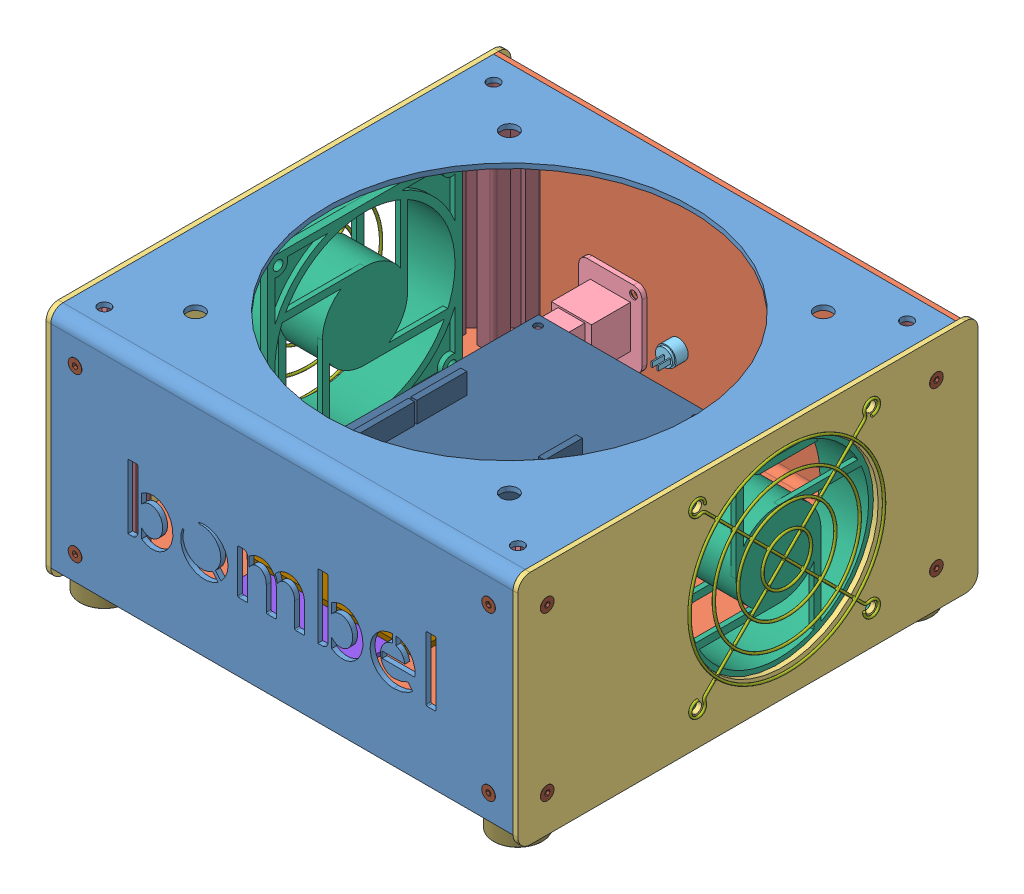
SolidWorks assembly 1 Case, configuration Domyślna. Lengths in mm.
Overall size (197.9 100.39 189.25).
41 component instances, 17 part files, 82 mates.
Components (placement in the parent):
- 1.1.2 top_panel_front-1: 1.1.2 top_panel_front [Domyślna] at origin size (190 92 182)
- 1.1.3 bottom_back-1: 1.1.3 bottom_back [Domyślna] at (0 -90 0) size (190 92 182)
- 1.1.4 side-1: 1.1.4 side [Domyślna] at (97 -94 27.8528) size (2 97 189.15)
- 1.1.4 side-2: 1.1.4 side [Domyślna] at (-95 -94 27.8528) size (2 97 189.15)
- 1.2.1 stop button-1: 1.2.1 stop button [Domyślna] at (-67.6862 -22.4205 120.7297) x (1 0 0) z (0 -0.573576 0.819152) size (37 74 39) (hidden)
- 1.2.4 usb-1: 1.2.4 usb [Domyślna] at (-45 -67 -90) x (-1 0 0) z (0 0 -1) size (26 31 41.5)
- 1.2.3 power socket-1: 1.2.3 power socket [Domyślna] at (-19 -67 -96) x (1 0 0) z (0 0 -1) size (10 10 17)
- 1.2.2 fan 80-1: 1.2.2 fan 80 [Domyślna] at (85 -46.7 -17.1472) x (0 0 1) z (-1 0 0) size (80 80 20.01)
- 1.2.2 fan 80-2: 1.2.2 fan 80 [Domyślna] at (-85 -46.7 -17.1472) x (0 0 -1) z (1 0 0) size (80 80 20.01)
- 1.2.9 fan barrier-1: 1.2.9 fan barrier [Domyślna] at (97.5 -46.7 -17.1472) x (0 0 -1) z (1 0 0) size (81 81 1.9)
- 1.2.6 screen-1: 1.2.6 screen [Domyślna] at (-6.25 -20.8447 110.4623) x (1 0 0) z (0 -0.573576 0.819152) size (77.5 14.2 42.8) (hidden)
- 1.2.7 joystick-1: 1.2.7 joystick [Domyślna] at (63.75 -22.9474 119.9159) x (1 0 0) z (0 -0.573576 0.819152) size (52.5 133.13 52.5) (hidden)
- 1.2.5 elektronika-1: 1.2.5 elektronika [Domyślna] at (-11.5 -80 35) x (0 0 -1) z (1 0 0) size (129 45 75.5)
  - 1.2.5.1 plytka podstawa-1: 1.2.5.1 plytka podstawa [Domyślna] at origin size (88 10 55)
  - 1.2.5.2 nucleo-f411re-1: 1.2.5.2 nucleo-f411re [Domyślna] at (1.6807 11.5 7.1981) x (-1 0 0) z (0 0 -1) size (82.5 19 70)
  - 1.2.5.3 x-nucleo-ihm02a1-1: 1.2.5.3 x-nucleo-ihm02a1 [Domyślna] at (39 23.5 11.5) size (92 18.5 73)
  - 1.2.5.3 x-nucleo-ihm02a1-2: 1.2.5.3 x-nucleo-ihm02a1 [Domyślna] at (39 35 11.5) size (92 18.5 73)
- 1.2.8 buttons-1: 1.2.8 buttons [Domyślna] at (-8.25 -47.2433 131.775) x (1 0 0) z (0 -0.573576 0.819152) size (76 7.6 17.4) (hidden)
- 1.2.9 fan barrier-2: 1.2.9 fan barrier [Domyślna] at (-97.5 -46.7 -17.1472) x (0 0 1) z (-1 0 0) size (81 81 1.9)
- socket csink head cap screw 10642_din-2: socket csink head cap screw 10642_din [EN ISO 10642 - M3 x 8 - 8N] at (85 -82 92.1) x (0 0 -1) z (-0.284698 0.958617 0) size (8 5.54 5.54)
- socket csink head cap screw 10642_din-3: socket csink head cap screw 10642_din [EN ISO 10642 - M3 x 8 - 8N] at (85 -15 92.1) x (0 0 -1) z (-0.433088 0.901352 0) size (8 5.54 5.54)
- socket csink head cap screw 10642_din-5: socket csink head cap screw 10642_din [EN ISO 10642 - M3 x 8 - 8N] at (97.1 -15 80) x (-1 0 0) z (0 0.725657 0.688057) size (8 5.54 5.54)
- socket csink head cap screw 10642_din-7: socket csink head cap screw 10642_din [EN ISO 10642 - M3 x 8 - 8N] at (97.1 -82 80) x (-1 0 0) z (0 0.659411 0.751782) size (8 5.54 5.54)
- socket csink head cap screw 10642_din-9: socket csink head cap screw 10642_din [EN ISO 10642 - M3 x 8 - 8N] at (-85 -15 92.1) x (0 0 -1) z (-0.661943 0.749554 0) size (8 5.54 5.54)
- socket csink head cap screw 10642_din-11: socket csink head cap screw 10642_din [EN ISO 10642 - M3 x 8 - 8N] at (-85 -82 92.1) x (0 0 -1) z (-0.669203 0.743079 0) size (8 5.54 5.54)
- socket csink head cap screw 10642_din-13: socket csink head cap screw 10642_din [EN ISO 10642 - M3 x 8 - 8N] at (-97.1 -15 80) x (1 0 0) z (0 0.345644 0.938366) size (8 5.54 5.54)
- socket csink head cap screw 10642_din-15: socket csink head cap screw 10642_din [EN ISO 10642 - M3 x 8 - 8N] at (-97.1 -82 80) x (1 0 0) z (0 0.223396 0.974728) size (8 5.54 5.54)
- socket csink head cap screw 10642_din-17: socket csink head cap screw 10642_din [EN ISO 10642 - M3 x 8 - 8N] at (-97.1 -15 -80) x (1 0 0) z (0 0.068735 0.997635) size (8 5.54 5.54)
- socket csink head cap screw 10642_din-19: socket csink head cap screw 10642_din [EN ISO 10642 - M3 x 8 - 8N] at (-97.1 -82 -80) x (1 0 0) z (0 -0.102923 0.994689) size (8 5.54 5.54)
- socket csink head cap screw 10642_din-21: socket csink head cap screw 10642_din [EN ISO 10642 - M3 x 8 - 8N] at (-85 -15 -92.1) x (0 0 1) z (0.113911 0.993491 0) size (8 5.54 5.54)
- socket csink head cap screw 10642_din-23: socket csink head cap screw 10642_din [EN ISO 10642 - M3 x 8 - 8N] at (85 -15 -92.1) x (0 0 1) z (-0.060338 0.998178 0) size (8 5.54 5.54)
- socket csink head cap screw 10642_din-25: socket csink head cap screw 10642_din [EN ISO 10642 - M3 x 8 - 8N] at (97.1 -15 -80) x (-1 0 0) z (0 0.986031 -0.166559) size (8 5.54 5.54)
- socket csink head cap screw 10642_din-27: socket csink head cap screw 10642_din [EN ISO 10642 - M3 x 8 - 8N] at (97.1 -82 -80) x (-1 0 0) z (0 0.96763 -0.252373) size (8 5.54 5.54)
- 1.1.8 foot-1: 1.1.8 foot [Domyślna] at (85 -100.3918 80) size (20 8.39 20)
- 1.1.8 foot-2: 1.1.8 foot [Domyślna] at (-85 -100.3918 80) x (0.982082 0 -0.188455) z (0.188455 0 0.982082) size (20 8.39 20)
- 1.1.8 foot-3: 1.1.8 foot [Domyślna] at (-85 -100.3918 -80) x (0.918365 0 -0.395734) z (0.395734 0 0.918365) size (20 8.39 20)
- 1.1.8 foot-4: 1.1.8 foot [Domyślna] at (85 -100.3918 -80) x (0.8 0 -0.6) z (0.6 0 0.8) size (20 8.39 20)
- 1.1.1 Profil 2020-3: 1.1.1 Profil 2020 [Domyślna] at (85 -87 -80) size (20 85 20)
- 1.1.1 Profil 2020-4: 1.1.1 Profil 2020 [Domyślna] at (-85 -87 -80) size (20 85 20)
- 1.1.1 Profil 2020-6: 1.1.1 Profil 2020 [Domyślna] at (-85 -5 80) x (1 0 0) z (0 0 -1) size (20 85 20)
- 1.1.1 Profil 2020-8: 1.1.1 Profil 2020 [Domyślna] at (85 -5 80) x (1 0 0) z (0 0 -1) size (20 85 20)
Mates (geometry in assembly coordinates):
- Wspólnie1: coordinate: point of 1.1.2 top_panel_front-1; point of assembly
- Wspólnie18: coincident anti-aligned: plane of 1.1.3 bottom_back-1 through (95 -90 -90) normal (0 0 1); plane of 1.2.4 usb-1 through (-45 -67 -90) normal (0 0 -1)
- Koncentryczne7: concentric anti-aligned: cylinder of 1.1.3 bottom_back-1 through (-45 -67 -82) axis (0 0 -1) radius 12; cylinder of 1.2.4 usb-1 through (-45 -67 -93) axis (0 0 1) radius 12
- Koncentryczne9: concentric aligned: cylinder of 1.1.3 bottom_back-1 through (-35.5 -55 -82) axis (0 0 -1) radius 1.75; cylinder of 1.2.4 usb-1 through (-35.5 -55 -90) axis (0 0 -1) radius 1.6
- Wspólnie19: coincident anti-aligned: plane of 1.1.3 bottom_back-1 through (95 -90 -92) normal (0 0 -1); plane of 1.2.3 power socket-1 through (-19 -71 -92) normal (0 0 1)
- Koncentryczne10: concentric aligned: cylinder of 1.1.3 bottom_back-1 through (-19 -67 -82) axis (0 0 -1) radius 4; cylinder of 1.2.3 power socket-1 through (-19 -67 -119.6978) axis (0 0 -1) radius 4
- Wspólnie20: coincident anti-aligned: plane of 1.1.4 side-1 through (95 -94 27.8528) normal (-1 0 0); plane of 1.2.2 fan 80-1 through (95 -46.7 -17.1472) normal (1 0 0)
- Koncentryczne11: concentric aligned: cylinder of 1.1.4 side-1 through (87 -10.95 -52.8972) axis (1 0 0) radius 2.1; cylinder of 1.2.2 fan 80-1 through (95 -10.95 -52.8972) axis (1 0 0) radius 2
- Koncentryczne12: concentric aligned: cylinder of 1.1.4 side-1 through (87 -10.95 18.6028) axis (1 0 0) radius 2.1; cylinder of 1.2.2 fan 80-1 through (95 -10.95 18.6028) axis (1 0 0) radius 2
- Wspólnie21: coincident anti-aligned: plane of 1.1.4 side-2 through (-95 -94 27.8528) normal (1 0 0); plane of 1.2.2 fan 80-2 through (-95 -46.7 -17.1472) normal (-1 0 0)
- Koncentryczne13: concentric anti-aligned: cylinder of 1.1.4 side-2 through (-105 -10.95 18.6028) axis (1 0 0) radius 2.1; cylinder of 1.2.2 fan 80-2 through (-95 -10.95 18.6028) axis (-1 0 0) radius 2
- Koncentryczne15: concentric anti-aligned: cylinder of 1.1.4 side-2 through (-105 -10.95 -52.8972) axis (1 0 0) radius 2.1; cylinder of 1.2.2 fan 80-2 through (-95 -10.95 -52.8972) axis (-1 0 0) radius 2
- Równolegle4: parallel aligned: plane of 1.2.5 elektronika-1/1.2.5.1 plytka podstawa-1 through (-11.5 -80 35) normal (0 1 0); plane of assembly through (0 0 0) normal (0 1 0)
- Wspólnie30: coincident aligned: plane of 1.1.3 bottom_back-1 through (95 0 -90) normal (0 1 0); plane of 1.1.2 top_panel_front-1 through (95 0 -90) normal (0 1 0)
- Wspólnie31: coincident anti-aligned: plane of 1.1.3 bottom_back-1 through (-95 -87 -87) normal (-1 0 0); plane of 1.1.4 side-2 through (-95 -94 27.8528) normal (1 0 0)
- Wspólnie34: coincident anti-aligned: plane of 1.1.2 top_panel_front-1 through (-95 -5 92) normal (-1 0 0); plane of 1.1.4 side-2 through (-95 -94 27.8528) normal (1 0 0)
- Wspólnie35: coincident anti-aligned: plane of 1.1.2 top_panel_front-1 through (95 -5 87) normal (1 0 0); plane of 1.1.4 side-1 through (95 -94 27.8528) normal (-1 0 0)
- Odległość3: distance = 10 mm anti-aligned: plane of 1.2.5 elektronika-1/1.2.5.1 plytka podstawa-1 through (-11.5 -80 35) normal (0 -1 0); plane of 1.1.3 bottom_back-1 through (95 -90 90) normal (0 1 0)
- Odległość4: distance = 40 mm anti-aligned: plane of 1.1.3 bottom_back-1 through (95 -90 -90) normal (0 0 1); plane of 1.2.5 elektronika-1/1.2.5.3 x-nucleo-ihm02a1-2 through (-36.5 -43.5 -50) normal (0 0 -1)
- Szerokość2: width anti-aligned: plane of 1.2.5 elektronika-1/1.2.5.3 x-nucleo-ihm02a1-2 through (36.5 -43.5 -50) normal (1 0 0); plane of 1.2.5 elektronika-1/1.2.5.3 x-nucleo-ihm02a1-2 through (-36.5 -43.5 42) normal (-1 0 0); plane of 1.1.4 side-2 through (-97 -94 27.8528) normal (-1 0 0); plane of 1.1.4 side-1 through (97 -94 27.8528) normal (1 0 0)
- Odległość5: distance = 0.5 mm aligned: plane of 1.2.9 fan barrier-1 through (97.5 -46.7 -17.1472) normal (1 0 0); plane of 1.1.4 side-1 through (97 -94 27.8528) normal (1 0 0)
- Równolegle5: parallel aligned: plane of 1.2.9 fan barrier-1 through (97.5 -46.7 -17.1472) normal (0 1 0); plane of assembly through (0 0 0) normal (0 1 0)
- Koncentryczne21: concentric aligned: cylinder of 1.1.4 side-1 through (87 -46.7 -17.1472) axis (1 0 0) radius 39; line of 1.2.9 fan barrier-1 through (96.95 -46.7 -17.1472) axis (1 0 0)
- Równolegle7: parallel aligned: plane of 1.2.1 stop button-1 through (-67.6862 -22.4205 120.7297) normal (1 0 0); plane of assembly through (0 0 0) normal (1 0 0)
- Równolegle8: parallel aligned: plane of 1.2.7 joystick-1 through (63.75 -22.9474 119.9159) normal (1 0 0); plane of assembly through (0 0 0) normal (1 0 0)
- Równolegle9: parallel aligned: plane of 1.2.3 power socket-1 through (-19 -67 -96) normal (1 0 0); plane of assembly through (0 0 0) normal (1 0 0)
- Odległość6: distance = 0.5 mm aligned: plane of 1.2.9 fan barrier-2 through (-97.5 -46.7 -17.1472) normal (-1 0 0); plane of 1.1.4 side-2 through (-97 -94 27.8528) normal (-1 0 0)
- Równolegle10: parallel aligned: plane of 1.2.9 fan barrier-2 through (-97.5 -46.7 -17.1472) normal (0 1 0); plane of assembly through (0 0 0) normal (0 1 0)
- Koncentryczne22: concentric anti-aligned: cylinder of 1.1.4 side-2 through (-105 -46.7 -17.1472) axis (1 0 0) radius 39; line of 1.2.9 fan barrier-2 through (-96.95 -46.7 -17.1472) axis (-1 0 0)
- Koncentryczne24: concentric aligned: cylinder of 1.1.2 top_panel_front-1 through (85 -82 82) axis (0 0 1) radius 1.5; cylinder of socket csink head cap screw 10642_din-2 through (85 -82 92.1) axis (0 0 1) radius 1.5
- Odległość7: distance = 0.1 mm aligned: plane of 1.1.2 top_panel_front-1 through (95 -2 92) normal (0 0 1); plane of socket csink head cap screw 10642_din-2 through (85 -82 92.1) normal (0 0 1)
- Koncentryczne25: concentric aligned: cylinder of 1.1.2 top_panel_front-1 through (85 -15 82) axis (0 0 1) radius 1.5; cylinder of socket csink head cap screw 10642_din-3 through (85 -15 92.1) axis (0 0 1) radius 1.5
- Odległość8: distance = 0.1 mm aligned: plane of 1.1.2 top_panel_front-1 through (95 -2 92) normal (0 0 1); plane of socket csink head cap screw 10642_din-3 through (85 -15 92.1) normal (0 0 1)
- Koncentryczne26: concentric aligned: cylinder of 1.1.4 side-1 through (87 -15 80) axis (1 0 0) radius 1.5; cylinder of socket csink head cap screw 10642_din-5 through (97.1 -15 80) axis (1 0 0) radius 1.5
- Odległość9: distance = 0.1 mm aligned: plane of 1.1.4 side-1 through (97 -94 27.8528) normal (1 0 0); plane of socket csink head cap screw 10642_din-5 through (97.1 -15 80) normal (1 0 0)
- Koncentryczne27: concentric aligned: cylinder of 1.1.4 side-1 through (87 -82 80) axis (1 0 0) radius 1.5; cylinder of socket csink head cap screw 10642_din-7 through (97.1 -82 80) axis (1 0 0) radius 1.5
- Odległość10: distance = 0.1 mm aligned: plane of 1.1.4 side-1 through (97 -94 27.8528) normal (1 0 0); plane of socket csink head cap screw 10642_din-7 through (97.1 -82 80) normal (1 0 0)
- Koncentryczne28: concentric aligned: cylinder of 1.1.2 top_panel_front-1 through (-85 -15 82) axis (0 0 1) radius 1.5; cylinder of socket csink head cap screw 10642_din-9 through (-85 -15 92.1) axis (0 0 1) radius 1.5
- Odległość11: distance = 0.1 mm aligned: plane of 1.1.2 top_panel_front-1 through (95 -2 92) normal (0 0 1); plane of socket csink head cap screw 10642_din-9 through (-85 -15 92.1) normal (0 0 1)
- Koncentryczne29: concentric aligned: cylinder of 1.1.2 top_panel_front-1 through (-85 -82 82) axis (0 0 1) radius 1.5; cylinder of socket csink head cap screw 10642_din-11 through (-85 -82 92.1) axis (0 0 1) radius 1.5
- Odległość12: distance = 0.1 mm aligned: plane of 1.1.2 top_panel_front-1 through (95 -2 92) normal (0 0 1); plane of socket csink head cap screw 10642_din-11 through (-85 -82 92.1) normal (0 0 1)
- Koncentryczne30: concentric anti-aligned: cylinder of 1.1.4 side-2 through (-105 -15 80) axis (1 0 0) radius 1.5; cylinder of socket csink head cap screw 10642_din-13 through (-97.1 -15 80) axis (-1 0 0) radius 1.5
- Odległość13: distance = 0.1 mm aligned: plane of 1.1.4 side-2 through (-97 -94 27.8528) normal (-1 0 0); plane of socket csink head cap screw 10642_din-13 through (-97.1 -15 80) normal (-1 0 0)
- Koncentryczne31: concentric anti-aligned: cylinder of 1.1.4 side-2 through (-105 -82 80) axis (1 0 0) radius 1.5; cylinder of socket csink head cap screw 10642_din-15 through (-97.1 -82 80) axis (-1 0 0) radius 1.5
- Odległość14: distance = 0.1 mm aligned: plane of 1.1.4 side-2 through (-97 -94 27.8528) normal (-1 0 0); plane of socket csink head cap screw 10642_din-15 through (-97.1 -82 80) normal (-1 0 0)
- Koncentryczne32: concentric anti-aligned: cylinder of 1.1.4 side-2 through (-105 -15 -80) axis (1 0 0) radius 1.5; cylinder of socket csink head cap screw 10642_din-17 through (-97.1 -15 -80) axis (-1 0 0) radius 1.5
- Odległość15: distance = 0.1 mm aligned: plane of 1.1.4 side-2 through (-97 -94 27.8528) normal (-1 0 0); plane of socket csink head cap screw 10642_din-17 through (-97.1 -15 -80) normal (-1 0 0)
- Koncentryczne33: concentric anti-aligned: cylinder of 1.1.4 side-2 through (-105 -82 -80) axis (1 0 0) radius 1.5; cylinder of socket csink head cap screw 10642_din-19 through (-97.1 -82 -80) axis (-1 0 0) radius 1.5
- Odległość16: distance = 0.1 mm aligned: plane of 1.1.4 side-2 through (-97 -94 27.8528) normal (-1 0 0); plane of socket csink head cap screw 10642_din-19 through (-97.1 -82 -80) normal (-1 0 0)
- Koncentryczne34: concentric aligned: cylinder of 1.1.3 bottom_back-1 through (-85 -15 -82) axis (0 0 -1) radius 1.5; cylinder of socket csink head cap screw 10642_din-21 through (-85 -15 -92.1) axis (0 0 -1) radius 1.5
- Odległość17: distance = 0.1 mm aligned: plane of 1.1.3 bottom_back-1 through (95 -90 -92) normal (0 0 -1); plane of socket csink head cap screw 10642_din-21 through (-85 -15 -92.1) normal (0 0 -1)
- Koncentryczne35: concentric aligned: cylinder of 1.1.3 bottom_back-1 through (85 -15 -82) axis (0 0 -1) radius 1.5; cylinder of socket csink head cap screw 10642_din-23 through (85 -15 -92.1) axis (0 0 -1) radius 1.5
- Odległość18: distance = 0.1 mm aligned: plane of 1.1.3 bottom_back-1 through (95 -90 -92) normal (0 0 -1); plane of socket csink head cap screw 10642_din-23 through (85 -15 -92.1) normal (0 0 -1)
- Koncentryczne36: concentric aligned: cylinder of 1.1.4 side-1 through (87 -15 -80) axis (1 0 0) radius 1.5; cylinder of socket csink head cap screw 10642_din-25 through (97.1 -15 -80) axis (1 0 0) radius 1.5
- Odległość19: distance = 0.1 mm aligned: plane of 1.1.4 side-1 through (97 -94 27.8528) normal (1 0 0); plane of socket csink head cap screw 10642_din-25 through (97.1 -15 -80) normal (1 0 0)
- Koncentryczne37: concentric aligned: cylinder of 1.1.4 side-1 through (87 -82 -80) axis (1 0 0) radius 1.5; cylinder of socket csink head cap screw 10642_din-27 through (97.1 -82 -80) axis (1 0 0) radius 1.5
- Odległość20: distance = 0.1 mm aligned: plane of 1.1.4 side-1 through (97 -94 27.8528) normal (1 0 0); plane of socket csink head cap screw 10642_din-27 through (97.1 -82 -80) normal (1 0 0)
- Wspólnie58: coincident aligned: plane of 1.1.3 bottom_back-1 through (95 -92 90) normal (0 -1 0); circle of 1.1.8 foot-1
- Koncentryczne38: concentric aligned: cylinder of 1.1.3 bottom_back-1 through (85 -100 80) axis (0 1 0) radius 2.5; cylinder of 1.1.8 foot-1 through (85 -91.9918 80) axis (0 1 0) radius 6.5
- Wspólnie59: coincident aligned: plane of 1.1.3 bottom_back-1 through (95 -92 90) normal (0 -1 0); circle of 1.1.8 foot-2
- Koncentryczne39: concentric aligned: cylinder of 1.1.3 bottom_back-1 through (-85 -100 80) axis (0 1 0) radius 2.5; cylinder of 1.1.8 foot-2 through (-85 -91.9918 80) axis (0 1 0) radius 6.5
- Wspólnie60: coincident aligned: plane of 1.1.3 bottom_back-1 through (95 -92 90) normal (0 -1 0); circle of 1.1.8 foot-3
- Koncentryczne40: concentric aligned: cylinder of 1.1.3 bottom_back-1 through (-85 -100 -80) axis (0 1 0) radius 2.5; cylinder of 1.1.8 foot-3 through (-85 -91.9918 -80) axis (0 1 0) radius 6.5
- Wspólnie61: coincident aligned: plane of 1.1.3 bottom_back-1 through (95 -92 90) normal (0 -1 0); circle of 1.1.8 foot-4
- Koncentryczne41: concentric aligned: cylinder of 1.1.3 bottom_back-1 through (85 -100 -80) axis (0 1 0) radius 2.5; cylinder of 1.1.8 foot-4 through (85 -91.9918 -80) axis (0 1 0) radius 6.5
- Wspólnie62: coincident aligned: plane of 1.1.2 top_panel_front-1 through (95 -2 92) normal (0 0 1); plane of 1.1.4 side-1 through (95 0 92) normal (0 0 1)
- Wspólnie63: coincident aligned: plane of 1.1.2 top_panel_front-1 through (95 0 -90) normal (0 1 0); plane of 1.1.4 side-1 through (95 0 -97.1472) normal (0 1 0)
- Wspólnie64: coincident aligned: plane of 1.1.2 top_panel_front-1 through (95 -2 92) normal (0 0 1); plane of 1.1.4 side-2 through (-97 0 92) normal (0 0 1)
- Wspólnie65: coincident aligned: plane of 1.1.2 top_panel_front-1 through (95 0 -90) normal (0 1 0); plane of 1.1.4 side-2 through (-97 0 -97.1472) normal (0 1 0)
- Koncentryczne42: concentric anti-aligned: cylinder of 1.1.3 bottom_back-1 through (85 -100 -80) axis (0 1 0) radius 2.5; cylinder of 1.1.1 Profil 2020-3 through (85 -2 -80) axis (0 -1 0) radius 2.5
- Koncentryczne43: concentric anti-aligned: cylinder of 1.1.2 top_panel_front-1 through (85 -10 -80) axis (0 1 0) radius 2.5; cylinder of 1.1.1 Profil 2020-3 through (85 -2 -80) axis (0 -1 0) radius 2.5
- Wspólnie66: coincident anti-aligned: plane of 1.1.3 bottom_back-1 through (95 -90 -90) normal (0 0 1); plane of 1.1.1 Profil 2020-3 through (85 -2 -90) normal (0 0 -1)
- Wspólnie67: coincident anti-aligned: plane of 1.1.2 top_panel_front-1 through (95 -2 -90) normal (0 -1 0); plane of 1.1.1 Profil 2020-3 through (85 -2 -80) normal (0 1 0)
- Koncentryczne44: concentric anti-aligned: cylinder of 1.1.3 bottom_back-1 through (-85 -100 -80) axis (0 1 0) radius 2.5; cylinder of 1.1.1 Profil 2020-4 through (-85 -2 -80) axis (0 -1 0) radius 2.5
- Wspólnie68: coincident anti-aligned: plane of 1.1.3 bottom_back-1 through (95 -90 -90) normal (0 0 1); plane of 1.1.1 Profil 2020-4 through (-85 -2 -90) normal (0 0 -1)
- Wspólnie69: coincident anti-aligned: plane of 1.1.2 top_panel_front-1 through (95 -2 -90) normal (0 -1 0); plane of 1.1.1 Profil 2020-4 through (-85 -2 -80) normal (0 1 0)
- Koncentryczne45: concentric aligned: cylinder of 1.1.2 top_panel_front-1 through (-85 -10 80) axis (0 1 0) radius 2.5; cylinder of 1.1.1 Profil 2020-6 through (-85 -90 80) axis (0 1 0) radius 2.5
- Wspólnie72: coincident anti-aligned: plane of 1.1.2 top_panel_front-1 through (95 -2 90) normal (0 0 -1); plane of 1.1.1 Profil 2020-6 through (-85 -90 90) normal (0 0 1)
- Wspólnie73: coincident anti-aligned: plane of 1.1.3 bottom_back-1 through (95 -90 90) normal (0 1 0); plane of 1.1.1 Profil 2020-6 through (-85 -90 80) normal (0 -1 0)
- Koncentryczne46: concentric aligned: cylinder of 1.1.2 top_panel_front-1 through (85 -10 80) axis (0 1 0) radius 2.5; cylinder of 1.1.1 Profil 2020-8 through (85 -90 80) axis (0 1 0) radius 2.5
- Wspólnie74: coincident anti-aligned: plane of 1.1.2 top_panel_front-1 through (95 -2 90) normal (0 0 -1); plane of 1.1.1 Profil 2020-8 through (85 -90 90) normal (0 0 1)
- Wspólnie75: coincident anti-aligned: plane of 1.1.3 bottom_back-1 through (95 -90 90) normal (0 1 0); plane of 1.1.1 Profil 2020-8 through (85 -90 80) normal (0 -1 0)
